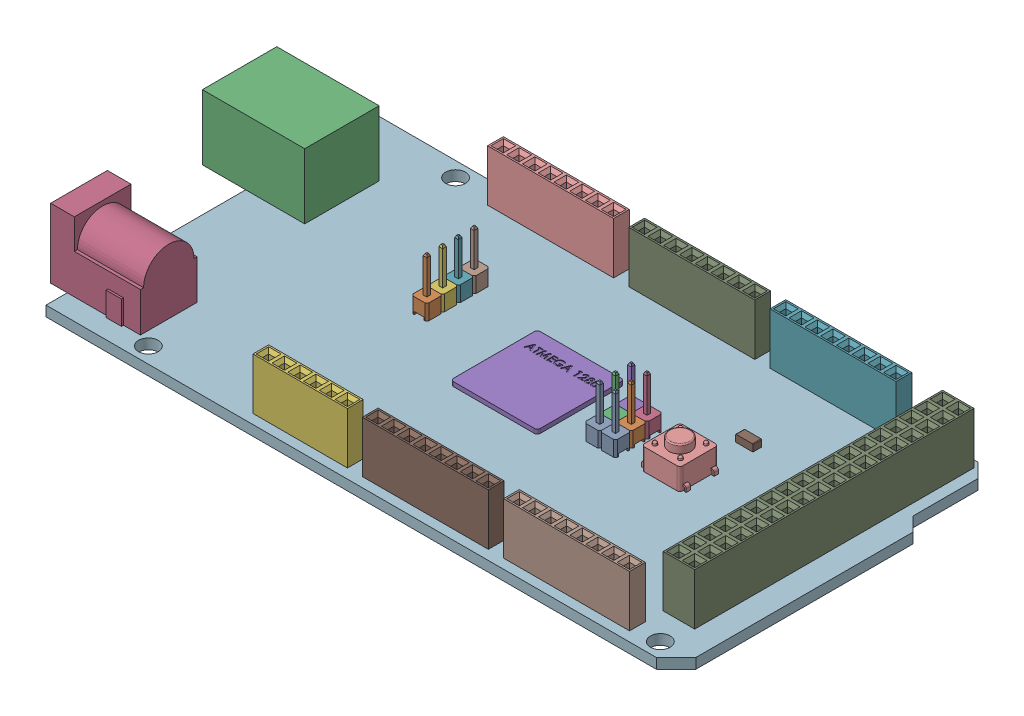
SolidWorks assembly 3-Arduino Mega Rev-3, configuration Default. Lengths in mm.
Overall size (108.58 14.9 53.21).
23 component instances, 12 part files, 0 mates.
Components (placement in the parent):
- 3-Part4-1: 3-Part4 [Default] at origin size (2.54 9.3 2.54)
- 3-Part20-13: 3-Part20 [Default] at origin size (2.54 9.3 2.54)
- 3-Part24-1: 3-Part24 [Default] at origin size (16.5 14.22 14.86)
- 3-Part26-1: 3-Part26 [Default] at origin size (14.48 14.78 9.47)
- 3-Part28-1: 3-Part28 [Default] at origin size (14 0.7 14)
- 3-Part30-1: 3-Part30 [Default] at origin size (15.24 8.3 2.54)
- 3-Part32-1: 3-Part32 [Default] at origin size (20.32 8.3 2.54)
- 3-Part40-3: 3-Part40 [Default] at origin size (20.32 8.3 2.54)
- 3-Part42-1: 3-Part42 [Default] at origin size (5.08 8.3 45.04)
- 3-Part44-1: 3-Part44 [Default] at origin size (7.9 7.35 6.2)
- 3-Part46-1: 3-Part46 [Default] at origin size (2.8 1.12 1.4)
- 3-PCB-FIXED-1: 3-PCB-FIXED [Default] at (0.1155 -4.6912 4.2705) x (1 0 0) z (0 0 -1) size (101.6 1.65 53.21)
- 3-Part4-7: 3-Part4 [Default] at (-2.54 0 0) size (2.54 9.3 2.54)
- 3-Part4-8: 3-Part4 [Default] at (0 0 -2.54) size (2.54 9.3 2.54)
- 3-Part4-9: 3-Part4 [Default] at (-2.54 0 -2.54) size (2.54 9.3 2.54)
- 3-Part4-10: 3-Part4 [Default] at (0 0 -5.08) size (2.54 9.3 2.54)
- 3-Part4-11: 3-Part4 [Default] at (-2.54 0 -5.08) size (2.54 9.3 2.54)
- 3-Part20-14: 3-Part20 [Default] at (0 0 -2.54) size (2.54 9.3 2.54)
- 3-Part20-15: 3-Part20 [Default] at (0 0 -5.08) size (2.54 9.3 2.54)
- 3-Part20-16: 3-Part20 [Default] at (0 0 -7.62) size (2.54 9.3 2.54)
- 3-Part32-6: 3-Part32 [Default] at (-22.77 0 0) size (20.32 8.3 2.54)
- 3-Part32-7: 3-Part32 [Default] at (-45.54 0 0) size (20.32 8.3 2.54)
- 3-Part40-4: 3-Part40 [Default] at (-22.77 0 0) size (20.32 8.3 2.54)
